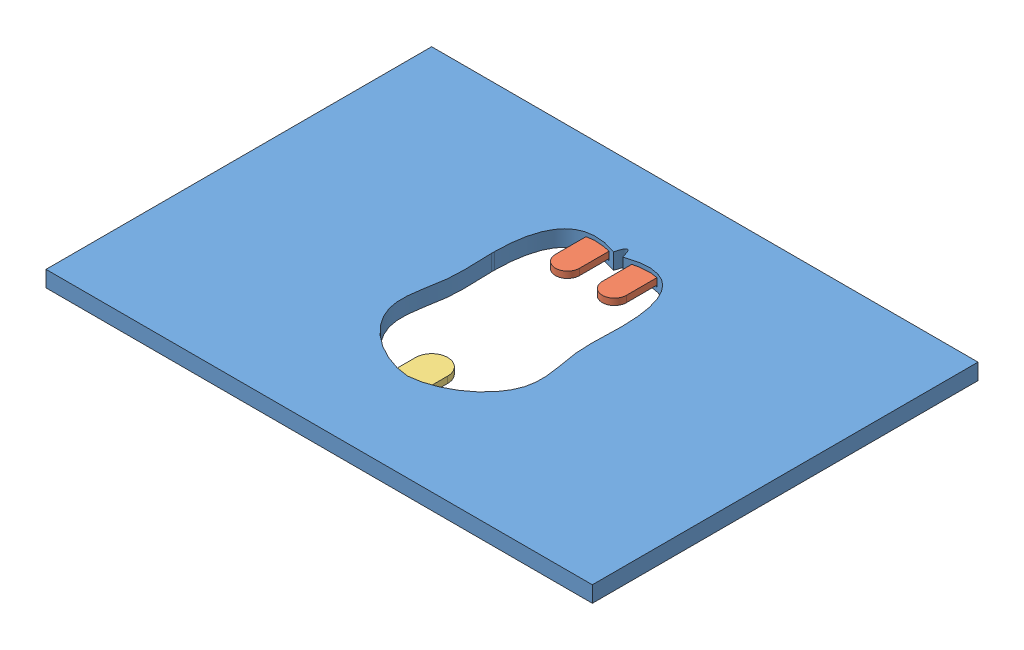
SolidWorks assembly 装配体1, configuration 默认. Lengths in mm.
Overall size (34 1 24).
4 component instances, 3 part files, 9 mates.
Components (placement in the parent):
- 盒盖-1: 盒盖 [默认] at (-2.6501 1.6466 0) size (34 1 24)
- 小夹-1: 小夹 [默认] at (-0.942 1.9966 -5.9125) x (-1 0 0) z (0 0 -1) size (1.9 0.51 4.02)
- 小夹-2: 小夹 [默认] at (-3.8583 1.9966 -5.9125) x (-1 0 0) z (0 0 -1) size (1.9 0.51 4.02)
- 大夹-1: 大夹 [默认] at (-2.6501 1.9966 6) size (2.4 0.51 4.01)
Mates (geometry in assembly coordinates):
- 重合2: coincident anti-aligned: plane of 盒盖-1 through (-2.6501 2.3966 5) normal (0 -1 0); plane of 大夹-1 through (-5.596 2.3966 5.5) normal (0 1 0)
- 重合6: coincident anti-aligned: plane of 盒盖-1 through (-1.4501 2.1466 6.8) normal (-1 0 0); plane of 大夹-1 through (-1.4501 2.3966 7) normal (1 0 0)
- LimitDistance2: limit distance = 1 mm: line of 大夹-1 through (-1.4501 2.3966 7) axis (0 -1 0); line of 盒盖-1 through (-1.4501 2.3966 8) axis (0 -1 0)
- 重合8: coincident anti-aligned: plane of 盒盖-1 through (-6.2758 2.3966 -5) normal (0 -1 0); plane of 小夹-2 through (-4.1083 2.3966 -4.9125) normal (0 1 0)
- 重合11: coincident anti-aligned: plane of 盒盖-1 through (-3.3583 2.0216 -5) normal (-1 0 0); plane of 小夹-2 through (-3.3583 2.3966 -4.9125) normal (1 0 0)
- LimitDistance3: limit distance = 0.8 mm: line of 小夹-2 through (-3.1583 2.3966 -7.2) axis (0 -1 0); line of 盒盖-1 through (-3.1583 1.8966 -8) axis (0 1 0)
- 重合16: coincident anti-aligned: plane of 盒盖-1 through (-6.2758 2.3966 -5) normal (0 -1 0); plane of 小夹-1 through (-1.192 2.3966 -4.9125) normal (0 1 0)
- 重合17: coincident anti-aligned: plane of 盒盖-1 through (-0.442 2.0216 -5) normal (-1 0 0); plane of 小夹-1 through (-0.442 2.3966 -4.9125) normal (1 0 0)
- LimitDistance5: limit distance = 0.8 mm: line of 小夹-1 through (-0.242 2.3966 -7.2) axis (0 -1 0); line of 盒盖-1 through (-0.2413 1.8966 -8) axis (0 1 0)
